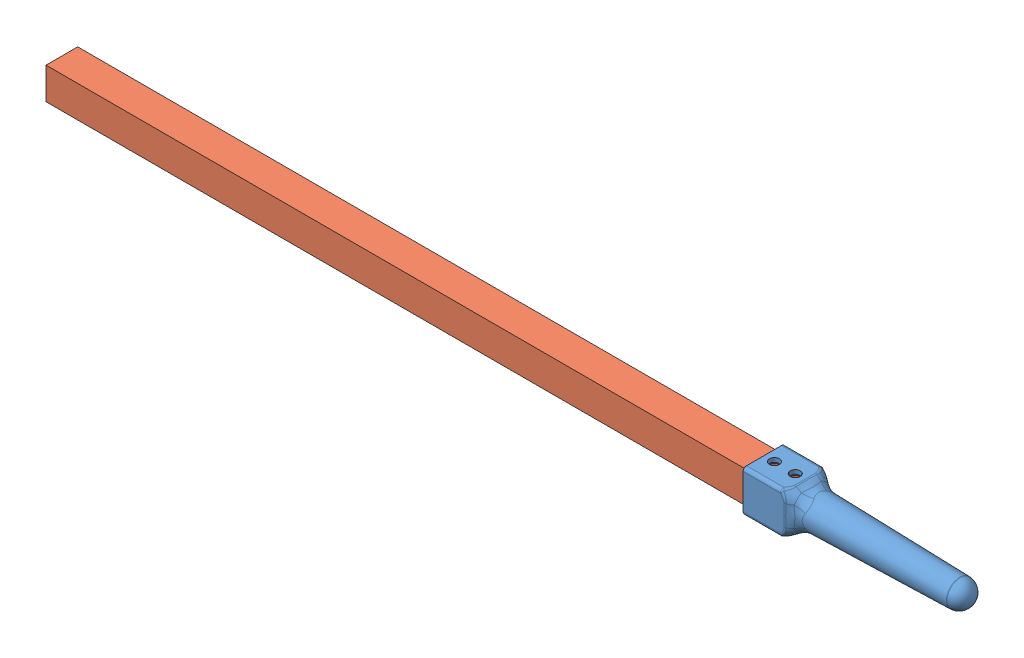
SolidWorks assembly Baton test assembly, configuration Default. Lengths in mm.
Overall size (546 25.7 25.7).
2 component instances, 2 part files, 2 mates.
Components (placement in the parent):
- baton-1: baton [Default] at (-168.1624 147.9962 287.5968) size (125 25.7 25.7)
- short key stick-1: short key stick [Default] at (-8.1631 147.9962 275.0965) x (0 0 1) z (-1 0 0) size (19 19 446)
Mates (geometry in assembly coordinates):
- Parallel2: parallel: plane of baton-1 through (-8.1631 147.9962 287.5968) normal (-1 0 0); plane of short key stick-1 through (-8.1631 147.9962 287.5968) normal (1 0 0)
- Concentric2: concentric: circle of baton-1; circle of short key stick-1
